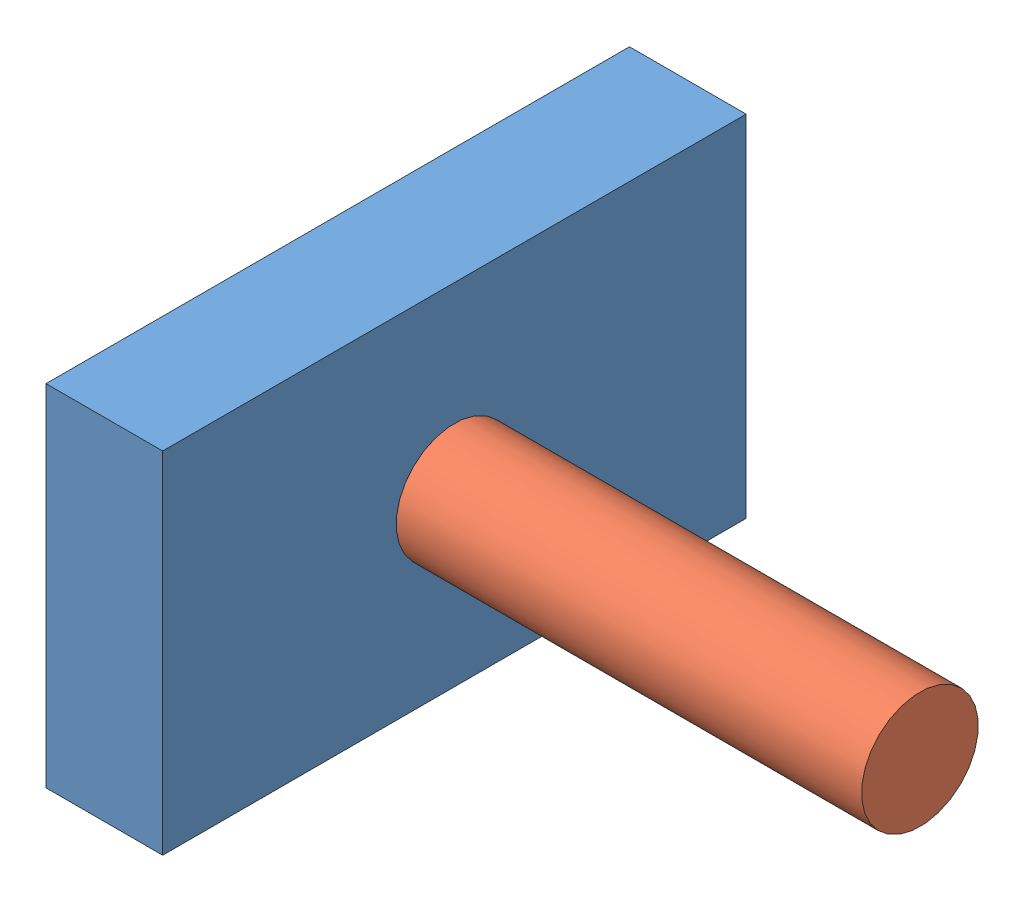
SolidWorks assembly Magnetic base, configuration Default. Lengths in mm.
Overall size (50 30 50).
2 component instances, 2 part files, 1 mates.
Components (placement in the parent):
- card-1: card [Default] at (10.9232 42.8222 68.5375) x (0 0 -1) z (1 0 0) size (50 30 10)
- Magnetic rod-1: Magnetic rod [Default] at (10.8054 27.3741 45.5694) x (1 0 0) z (0 -0.696613 0.717447) size (50 10 10)
Mates (geometry in assembly coordinates):
- Concentric1: concentric: circle of assembly; circle of assembly; circle of card-1; circle of Magnetic rod-1
